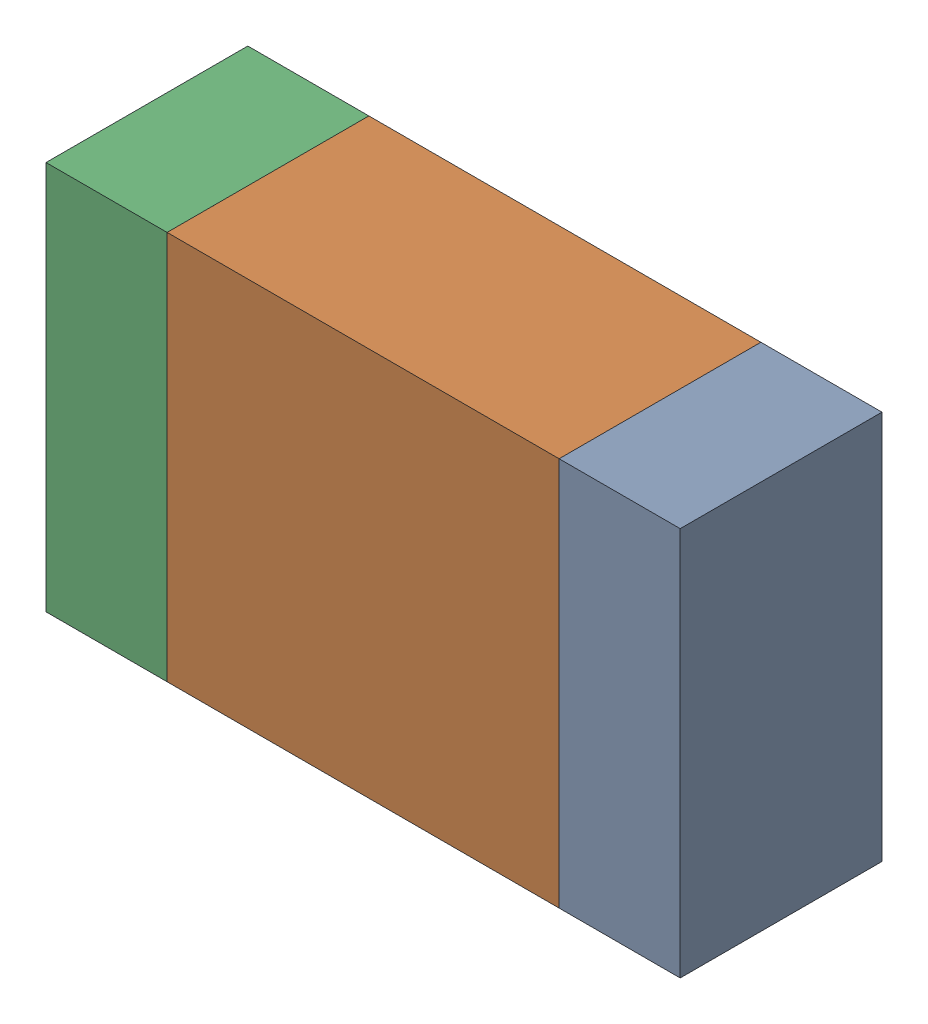
SolidWorks assembly R7, configuration Default. Lengths in mm.
Overall size (2.2 1.35 0.7).
6 component instances, 2 part files, 0 mates.
Components (placement in the parent):
- 959209344-1: 959209344 [Default] at (76.5821 79.5961 0) size (0.42 1.35 0.7)
  - Extruded-25-1: Extruded-25 [Default] at origin size (0.42 1.35 0.7)
- 959209480-1: 959209480 [Default] at (75.6921 79.5961 0) size (1.36 1.35 0.7)
  - Extruded-26-1: Extruded-26 [Default] at origin size (1.36 1.35 0.7)
- 959209344-2: 959209344 [Default] at (74.8021 79.5961 0) size (0.42 1.35 0.7)
  - Extruded-25-1: Extruded-25 [Default] at origin size (0.42 1.35 0.7)
